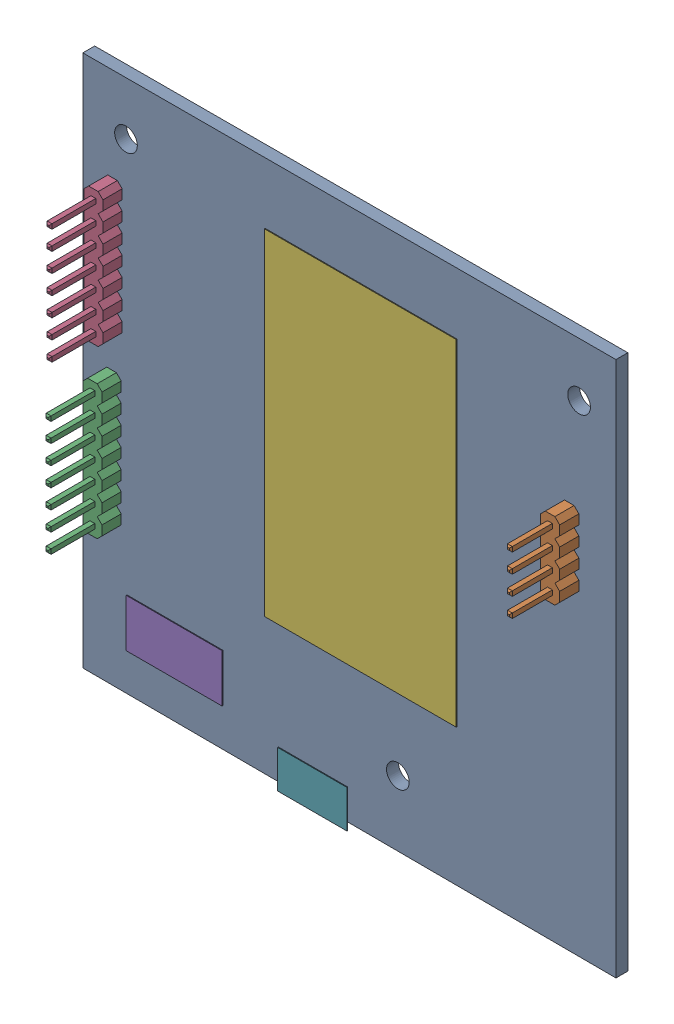
SolidWorks assembly PCB Component, configuration Standard. Lengths in mm.
Overall size (70.59 71.77 11.84).
7 component instances, 6 part files, 0 mates.
Components (placement in the parent):
- Board-1: Board [Standard] at origin size (70.59 70.92 1.57)
- 1X04-1: 1X04 [Standard] at (64.389 46.101 1.57) x (0 -1 0) z (0 0 1) size (10.16 2.54 11.34)
- 1X07-1: 1X07 [Standard] at (3.81 27.178 1.57) x (0 -1 0) z (0 0 1) size (17.78 2.54 11.54)
- 1X07-2: 1X07 [Standard] at (3.937 49.276 1.57) x (0 -1 0) z (0 0 1) size (17.78 2.54 11.54)
- 22-23-2051-1: 22-23-2051 [Standard] at (12.192 8.128 1.57) x (-1 0 0) z (0 0 1) size (12.7 6.35 0.1)
- ESP32-DEVKITV1-1: ESP32-DEVKITV1 [Standard] at (36.83 40.894 1.57) size (25.4 44.45 0.1)
- USB-MICRO-SMD-1: USB-MICRO-SMD [Standard] at (30.48 0.889 1.57) x (0 1 0) z (0 0 1) size (5 9.17 0.1)
